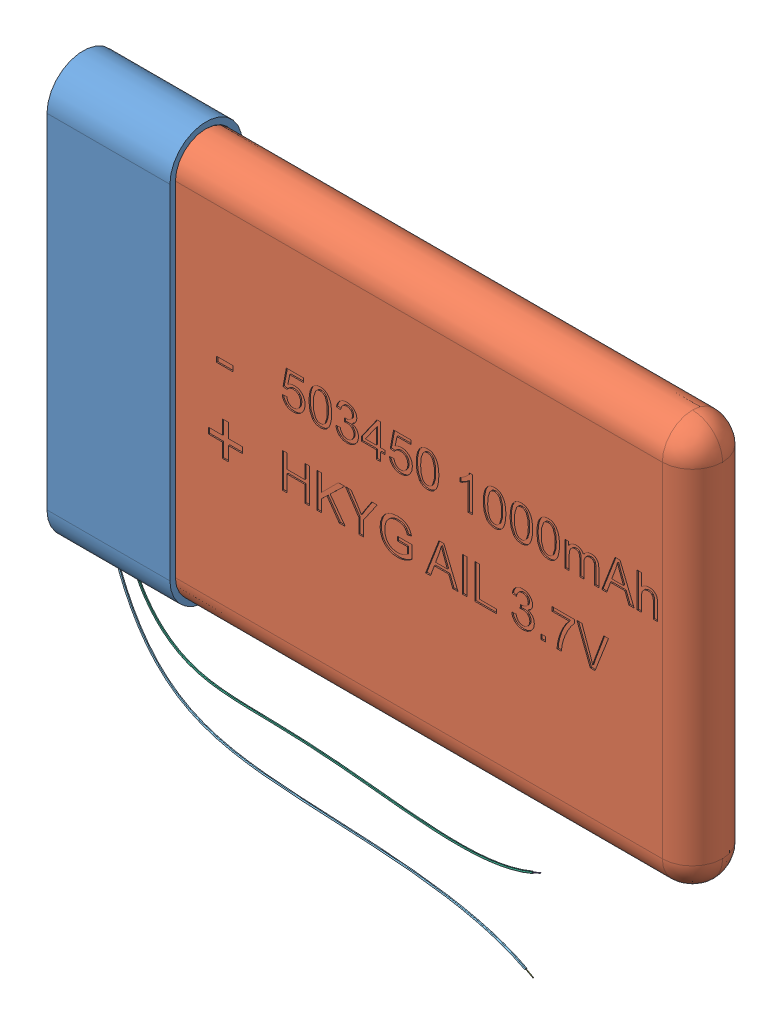
SolidWorks assembly Unnamed-Bateria LiPo 3.7V 1000mA 503450 v23, configuration Predeterminado. Lengths in mm.
Overall size (53.36 46.82 6).
9 component instances, 8 part files, 0 mates.
Components (placement in the parent):
- parte de la pila_lipo v4_1-1: parte de la pila_lipo v4_1 [Predeterminado] at (-27.4003 0 2.4569) x (0 1 0) z (-1 0 0) size (34.5 6 10.2)
- COMPOUND007_1-1: COMPOUND007_1 [Predeterminado] at origin size (50.86 46.58 5.52)
  - COMPOUND_1-1: COMPOUND_1 [Predeterminado] at origin size (50.86 34.02 5.52)
  - COMPOUND001_1-1: COMPOUND001_1 [Predeterminado] at origin size (3 9 0.2)
  - COMPOUND002_1-1: COMPOUND002_1 [Predeterminado] at origin size (3 9 0.2)
  - COMPOUND003_1-1: COMPOUND003_1 [Predeterminado] at origin size (34.86 31.57 0.38)
  - COMPOUND004_1-1: COMPOUND004_1 [Predeterminado] at origin size (34.64 21.24 0.38)
  - COMPOUND005_1-1: COMPOUND005_1 [Predeterminado] at origin size (0.64 0.37 0.05)
  - COMPOUND006_1-1: COMPOUND006_1 [Predeterminado] at origin size (0.66 0.32 0.05)
